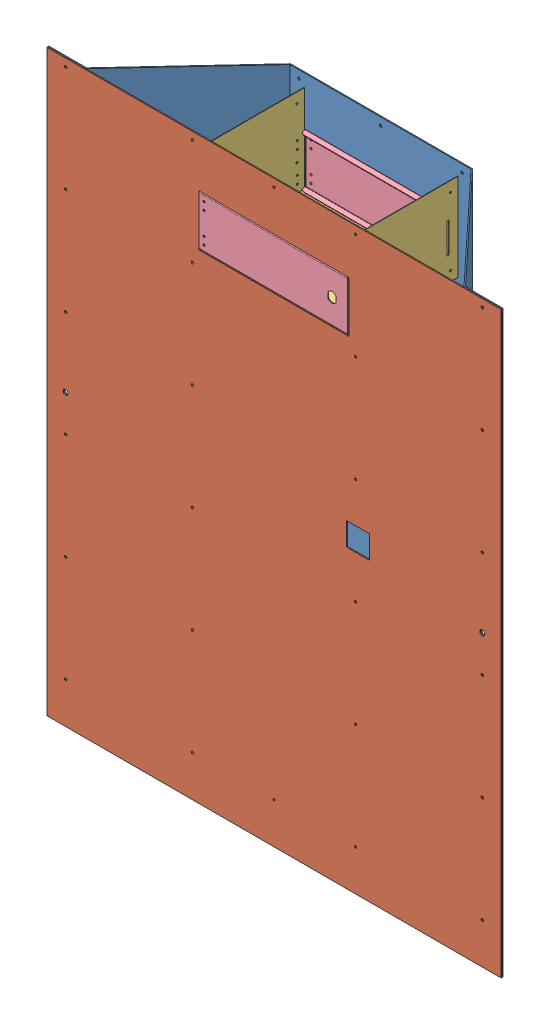
SolidWorks assembly aase, configuration По умолчанию. Lengths in mm.
Overall size (891.01 1135 210.97).
8 component instances, 7 part files, 21 mates.
Components (placement in the parent):
- frame-1: frame [По умолчанию] at (200.2583 321.2334 804.4239) size (352 1070 357) (hidden)
- face-1: face [По умолчанию] at (197.9381 256.2334 597.4239) size (891.01 1135 208.97)
- plate-1: plate [По умолчанию] at (-70.0564 256.2334 806.397) size (891 1135 2)
- shelf-1: shelf [По умолчанию] at (-72.0564 1407.2334 806.397) x (1 0 0) z (0 0 -1) size (895 16 215) (hidden)
- tray-1: tray [По умолчанию] at (225.2583 1194.2334 804.397) size (302 173 207)
- door-1: door [По умолчанию] at (519.2583 1197.2334 595.4239) x (-1 0 0) z (0 0 -1) size (292 98 12)
- door-2: door [По умолчанию] at (519.2583 1295.2334 806.397) x (-1 0 0) z (0 0 1) size (292 98 12)
- wall-mount-1: wall-mount [По умолчанию] at (15.4436 794.7809 1027.5455) x (0 0 1) z (0 1 0) size (40 40 100) (hidden)
Mates (geometry in assembly coordinates):
- Совпадение1: coincident anti-aligned: plane of frame-1 through (200.2583 346.2334 597.4239) normal (0 0 -1); plane of face-1 through (197.9381 256.2334 597.4239) normal (0 0 1)
- Совпадение2: coincident aligned: plane of frame-1 through (200.2583 1391.2334 804.4239) normal (0 1 0); plane of face-1 through (196.4753 1391.2334 596.0599) normal (0 1 0)
- Расстояние1: distance = 2 mm: line of face-1 through (198.2583 256.2334 597.4239) axis (0 1 0); plane of frame-1 through (200.2583 346.2334 804.4239) normal (-1 0 0)
- Совпадение11: coincident aligned: plane of face-1 through (820.9436 1391.2334 804.397) normal (1 0 0); plane of plate-1 through (820.9436 256.2334 804.397) normal (1 0 0)
- Совпадение12: coincident aligned: plane of face-1 through (746.8132 1391.2334 804.397) normal (0 1 0); plane of plate-1 through (-70.0564 1391.2334 804.397) normal (0 1 0)
- Совпадение14: coincident anti-aligned: plane of face-1 through (197.9381 256.2334 804.397) normal (0 0 1); plane of plate-1 through (-70.0564 256.2334 804.397) normal (0 0 -1)
- Совпадение15: coincident anti-aligned: plane of frame-1 through (200.2583 1391.2334 804.4239) normal (0 1 0); plane of shelf-1 through (-22.0564 1391.2334 641.397) normal (0 -1 0)
- Совпадение16: coincident aligned: plane of plate-1 through (-70.0564 256.2334 806.397) normal (0 0 1); plane of shelf-1 through (-72.0564 1391.2334 806.397) normal (0 0 1)
- Расстояние2: distance = 2 mm aligned: plane of plate-1 through (820.9436 256.2334 804.397) normal (1 0 0); plane of shelf-1 through (822.9436 1391.2334 806.397) normal (1 0 0)
- Совпадение18: coincident anti-aligned: plane of frame-1 through (225.2583 1391.2334 597.4239) normal (1 0 0); plane of tray-1 through (225.2583 1194.2334 804.397) normal (-1 0 0)
- Совпадение19: coincident anti-aligned: plane of plate-1 through (-70.0564 256.2334 804.397) normal (0 0 -1); plane of tray-1 through (225.2583 1193.2334 804.397) normal (0 0 1)
- Совпадение20: coincident: plane of frame-1 through (200.2583 1366.2334 804.4239) normal (0 -1 0); line of tray-1 through (226.2583 1366.2334 804.397) axis (0 0 -1)
- Совпадение21: coincident aligned: plane of face-1 through (197.9381 256.2334 595.4239) normal (0 0 -1); plane of door-1 through (519.2583 1197.2334 595.4239) normal (0 0 -1)
- Расстояние3: distance = 1 mm anti-aligned: plane of door-1 through (519.2583 1295.2334 595.4239) normal (0 1 0); plane of face-1 through (522.6178 1296.2334 804.398) normal (0 -1 0)
- Расстояние4: distance = 1 mm: line of face-1 through (228.2583 1196.2334 595.4239) axis (0 1 0); line of door-1 through (227.2583 1199.17 595.4239) axis (0 1 0)
- Совпадение24: coincident aligned: plane of door-1 through (519.2583 1295.2334 595.4239) normal (0 1 0); plane of door-2 through (519.2583 1295.2334 806.397) normal (0 1 0)
- Совпадение25: coincident aligned: plane of plate-1 through (-70.0564 256.2334 806.397) normal (0 0 1); plane of door-2 through (519.2583 1295.2334 806.397) normal (0 0 1)
- Совпадение26: coincident aligned: plane of door-1 through (227.2583 1197.2334 596.6239) normal (-1 0 0); plane of door-2 through (227.2583 1295.2334 805.197) normal (-1 0 0)
- Совпадение28: coincident: plane of wall-mount-1 through (15.4436 894.7809 1067.5455) normal (-1 0 0); line of assembly
- Параллельность3: parallel aligned: plane of shelf-1 through (-72.0564 1391.2334 806.397) normal (-1 0 0); plane of wall-mount-1 through (15.4436 894.7809 1067.5455) normal (-1 0 0)
- Параллельность4: parallel aligned: plane of plate-1 through (-70.0564 256.2334 806.397) normal (0 0 1); plane of wall-mount-1 through (55.4436 894.7809 1030.5455) normal (0 0 1)
